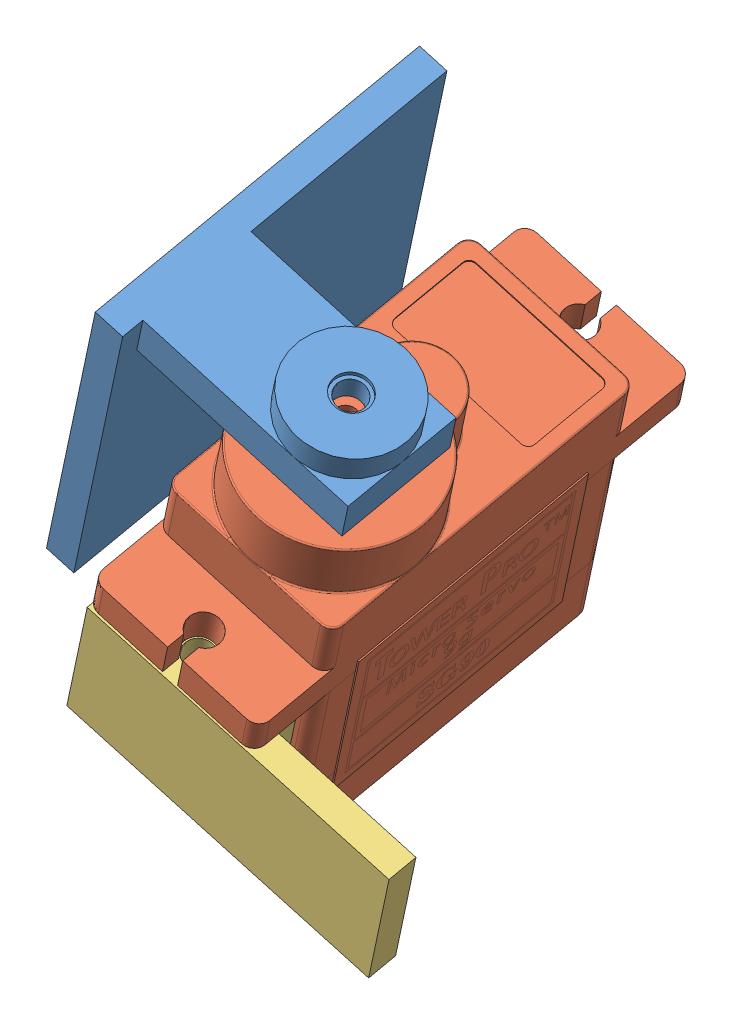
SolidWorks assembly Assem4, configuration Default. Lengths in mm.
Overall size (30.45 42.9 38.46).
3 component instances, 3 part files, 4 mates.
Components (placement in the parent):
- cam mount-1: cam mount [Default] at (-17.7592 5.162 32.7233) x (-0.359813 -0.908842 -0.211046) z (-0.013323 -0.221168 0.975145) size (26 17 24)
- SG90 - Micro Servo 9g - Tower Pro.1-2: SG90 - Micro Servo 9g - Tower Pro.1 [Peça] at (-2.7343 7.8951 33.4722) x (0.013323 0.221168 -0.975145) z (0.932929 -0.353682 -0.067471) size (32.1 29.95 12.4)
- cam base-2: cam base [Default] at (-10.6563 -6.0433 46.8268) x (-0.359813 -0.908842 -0.211046) z (0.932968 -0.352955 -0.070664) size (10 4.7 22)
Mates (geometry in assembly coordinates):
- Concentric2: concentric aligned: cylinder of cam mount-1 through (4.3656 24.863 42.6988) axis (0.359813 0.908842 0.211046) radius 1; cylinder of SG90 - Micro Servo 9g - Tower Pro.1-2 through (4.1415 24.2968 42.5673) axis (0.359813 0.908842 0.211046) radius 0.8
- Parallel5: parallel aligned: line of cam mount-1 through (-5.6501 32.8451 25.4008) axis (-0.013323 -0.221168 0.975145); line of SG90 - Micro Servo 9g - Tower Pro.1-2 through (-3.8935 23.178 26.2575) axis (-0.013323 -0.221168 0.975145)
- Concentric4: concentric anti-aligned: circle of SG90 - Micro Servo 9g - Tower Pro.1-2; circle of cam base-2
- Coincident8: coincident anti-aligned: plane of SG90 - Micro Servo 9g - Tower Pro.1-2 through (3.8141 7.3571 49.027) normal (-0.359813 -0.908842 -0.211046); plane of cam base-2 through (-6.574 11.5172 48.823) normal (0.359813 0.908842 0.211046)
